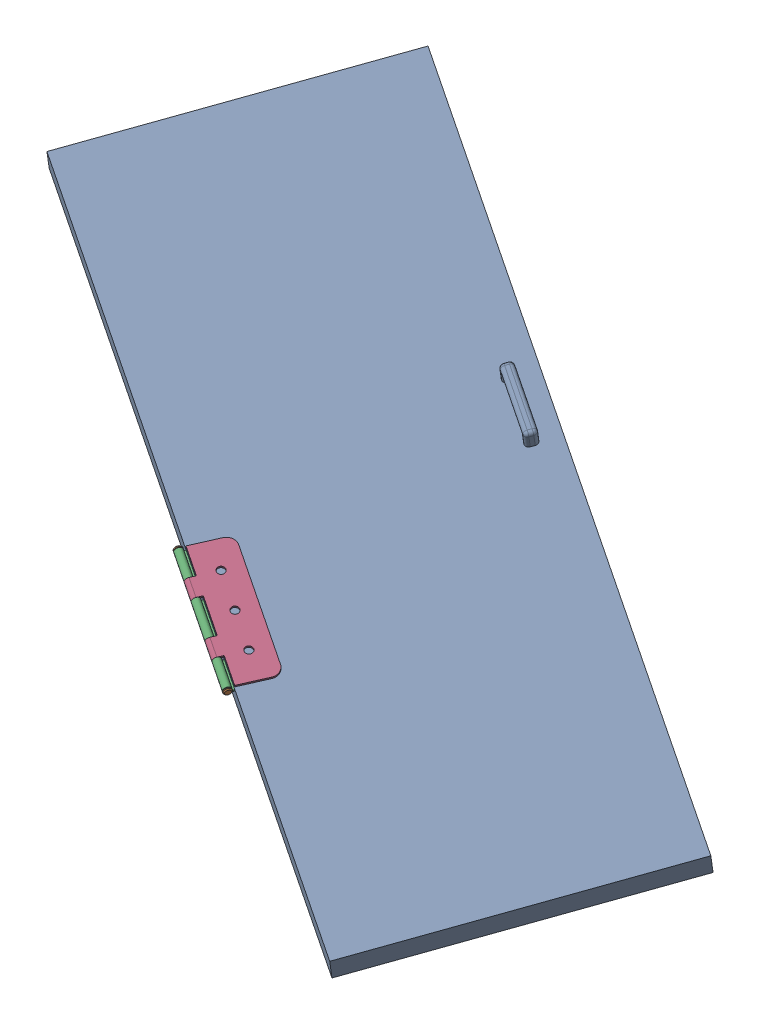
SolidWorks assembly New Right door with hinge, configuration Default. Lengths in mm.
Overall size (2120.35 854.12 1605.36).
5 component instances, 4 part files, 3 mates.
Components (placement in the parent):
- Door RIGHT side. For Building-1: Door RIGHT side. For Building [Default] at (218.7979 848.2764 588.2492) x (-0.515003 -0.161961 0.841749) z (0.185287 0.937739 0.293793) size (775 2032 111.15)
- Hinge Assembly-1: Hinge Assembly [Default] at (-121.2286 1030.3571 433.0668) x (0.517911 0.176995 -0.836924) z (0.836924 -0.30727 0.452929) size (126.38 32.59 362.5) (flexible)
  - Pin for Door-1: Pin for Door [Default] at origin size (20 20 362.5)
  - Door Hinge-1: Door Hinge [Default] at (60.3313 -6.5224 35.0125) x (0 0 -1) z (0.016055 0.999871 0) size (350 125 20)
  - Door Hinge Part 2-1: Door Hinge Part 2 [Default] at (68.1245 -0.62 -34.9875) x (0 0 1) z (-0.101576 -0.994828 0) size (350 125 20)
Mates (geometry in assembly coordinates):
- Coincident1: coincident aligned: plane of Door RIGHT side. For Building-1 through (229.3871 901.8682 605.0395) normal (0.185287 0.937739 0.293793); plane of Hinge Assembly-1/Door Hinge-1 through (83.5423 990.5179 414.0649) normal (0.185287 0.937739 0.293793)
- Distance1: distance = 100 mm anti-aligned: plane of Hinge Assembly-1/Door Hinge-1 through (-210.3074 1093.3735 254.0709) normal (0.515003 0.161961 -0.841749); plane of Door RIGHT side. For Building-1 through (229.3871 901.8682 605.0395) normal (-0.515003 -0.161961 0.841749)
- Distance2: distance = 1000 mm aligned: plane of Hinge Assembly-1/Door Hinge-1 through (-274.6827 1073.1284 359.2895) normal (-0.836924 0.30727 -0.452929); plane of Door RIGHT side. For Building-1 through (-698.6778 1514.6553 -765.5692) normal (-0.836924 0.30727 -0.452929)
